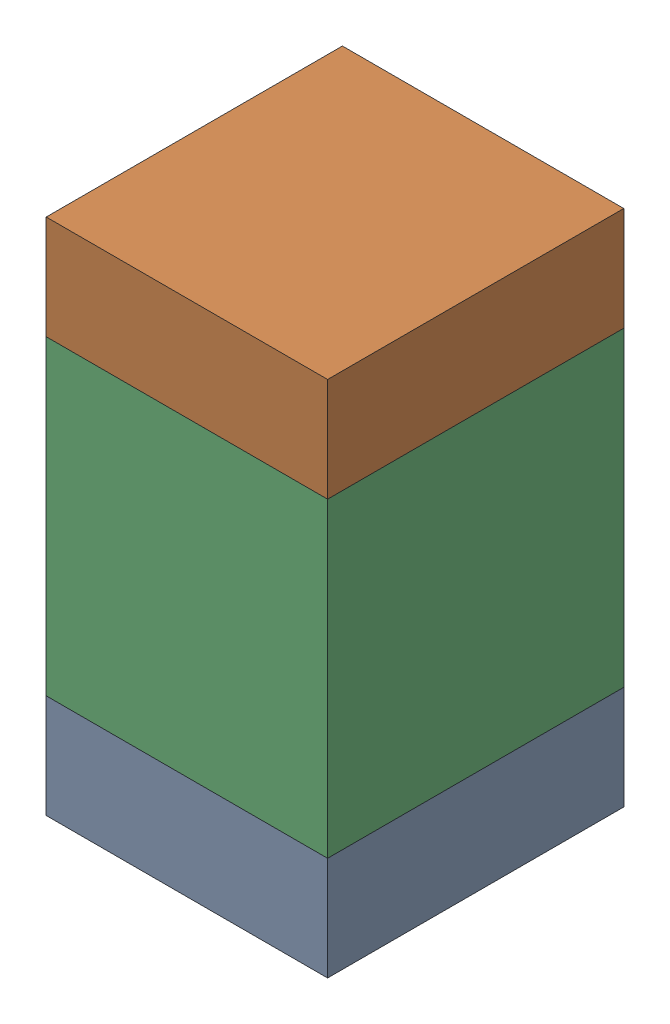
SolidWorks assembly C11-2, configuration Default. Lengths in mm.
Overall size (0.95 1.75 1).
6 component instances, 2 part files, 0 mates.
Components (placement in the parent):
- 959208664-2-1: 959208664-2 [Default] at (122.4827 75.652 0) size (0.95 0.35 1)
  - Extruded-76-1: Extruded-76 [Default] at origin size (0.95 0.35 1)
- 959208664-2-2: 959208664-2 [Default] at (122.4827 77.052 0) size (0.95 0.35 1)
  - Extruded-76-1: Extruded-76 [Default] at origin size (0.95 0.35 1)
- 959208528-2-1: 959208528-2 [Default] at (122.4827 76.352 0) size (0.95 1.05 1)
  - Extruded-77-1: Extruded-77 [Default] at origin size (0.95 1.05 1)
